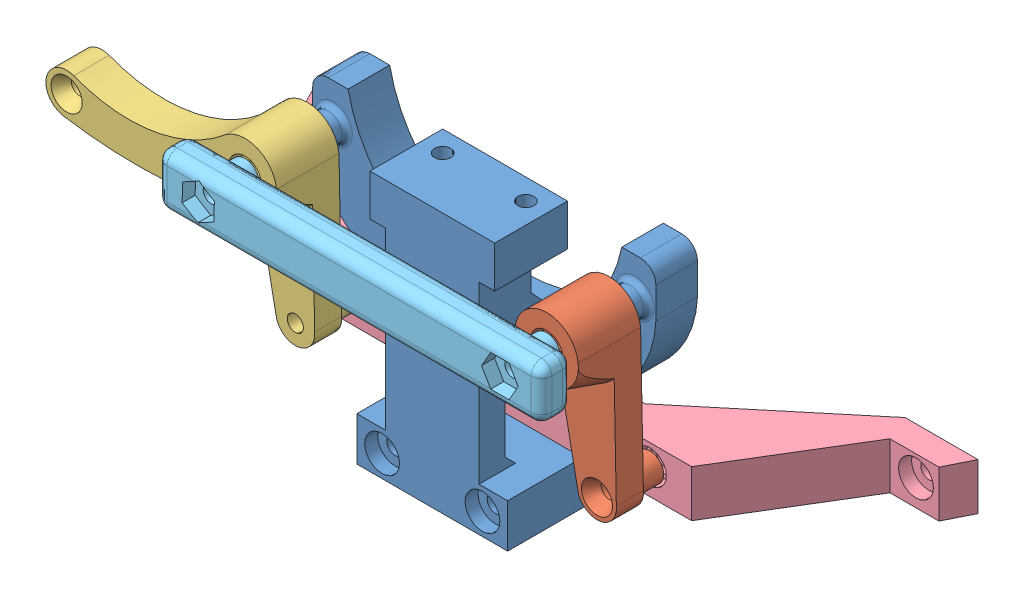
SolidWorks assembly 装配体2, configuration 默认. Lengths in mm.
Overall size (134.15 51.6 54.71).
5 component instances, 5 part files, 11 mates.
Components (placement in the parent):
- hgq_1_1-1: hgq_1_1 [默认] at (-0.2016 1.4966 57) size (66 51.6 18)
- hgq_2_1-1: hgq_2_1 [默认] at (30.0723 19.9739 70) x (0.994278 0.106824 0) z (0 0 1) size (13.81 36.65 17)
- hgq_3_1-1: hgq_3_1 [默认] at (-27.9277 19.9739 70) x (0.994278 0.106824 0) z (0 0 1) size (45.1 36.65 17)
- hgq_4_1-1: hgq_4_1 [默认] at (37.7465 -11.6728 51.9472) x (-1 0 0) z (0 1 0) size (126.71 28.71 9)
- hgq_5_1-1: hgq_5_1 [默认] at (-11.8281 21.309 91) x (1 0 0) z (0 0 -1) size (74 10 9)
Mates (geometry in assembly coordinates):
- 同心1: concentric anti-aligned: circle of hgq_1_1-1; circle of hgq_2_1-1
- 重合2: coincident anti-aligned: circle of hgq_1_1-1; plane of hgq_2_1-1 through (32.9352 -6.6728 70) normal (0 0 -1)
- 同心2: concentric anti-aligned: circle of hgq_1_1-1; circle of hgq_3_1-1
- 重合4: coincident anti-aligned: plane of hgq_1_1-1 through (-27.9277 19.9739 70) normal (0 0 1); plane of hgq_3_1-1 through (-25.0648 -6.6728 70) normal (0 0 -1)
- 同心3: concentric anti-aligned: circle of hgq_3_1-1; circle of hgq_5_1-1
- 重合5: coincident anti-aligned: plane of hgq_3_1-1 through (-25.0648 -6.6728 82) normal (0 0 1); plane of hgq_5_1-1 through (-27.9277 19.9739 82) normal (0 0 -1)
- 同心4: concentric anti-aligned: circle of hgq_2_1-1; circle of hgq_5_1-1
- 重合6: coincident anti-aligned: plane of hgq_2_1-1 through (32.9352 -6.6728 65) normal (0 0 -1); circle of hgq_4_1-1
- 重合7: coincident anti-aligned: plane of hgq_2_1-1 through (32.9352 -6.6728 65) normal (0 0 -1); plane of hgq_4_1-1 through (40.9352 -1.6728 65) normal (0 0 1)
- 同心5: concentric aligned: circle of hgq_2_1-1; circle of hgq_4_1-1
- 同心6: concentric anti-aligned: circle of hgq_3_1-1; circle of hgq_4_1-1
